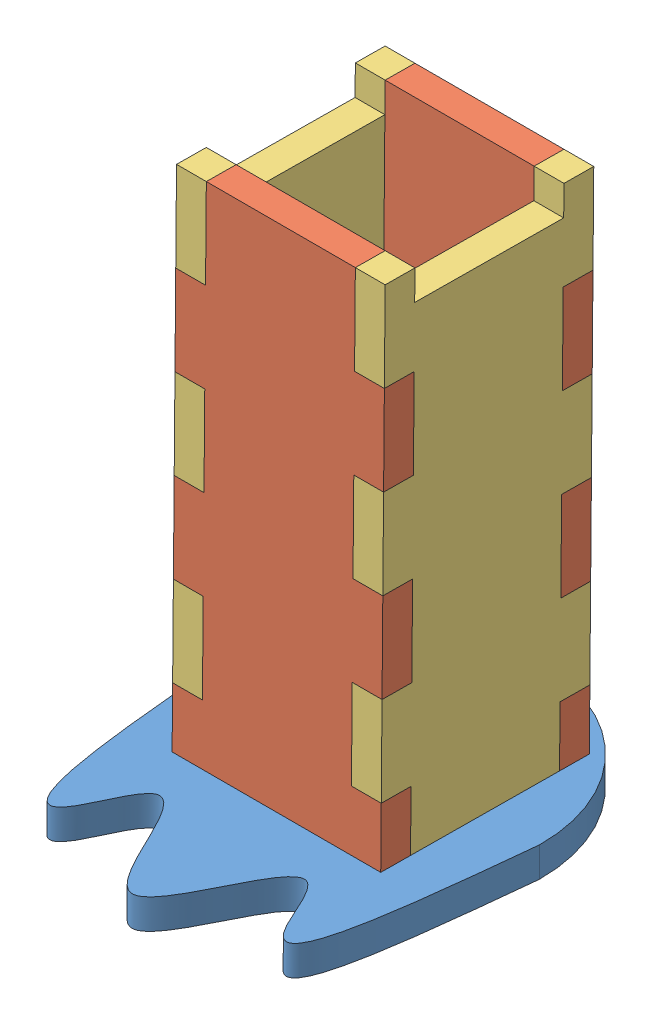
SolidWorks assembly short_leg, configuration Default. Lengths in mm.
Overall size (64 108.46 82.05).
5 component instances, 3 part files, 12 mates.
Components (placement in the parent):
- foot-1: foot [Default] at (-37.6359 -18.0496 -13.4582) x (1 0 0) z (0 -0.999962 0.008727) size (64 82 6)
- short_leg_front-1: short_leg_front [Default] at (48.8798 -33.2664 47.6015) x (-1 0 0) z (0 -0.008727 -0.999962) size (42 108 6)
- short_leg_right-1: short_leg_right [Default] at (29.3804 -31.3727 -13.2389) x (0 0.008727 0.999962) z (-1 0 0) size (42 108 6)
- short_leg_front-2: short_leg_front [Default] at (-32.119 -33.6329 5.6031) x (1 0 0) z (0 0.008727 0.999962) size (42 108 6)
- short_leg_right-2: short_leg_right [Default] at (-12.6196 -30.6777 66.4012) x (0 -0.008727 -0.999962) z (1 0 0) size (42 108 6)
Mates (geometry in assembly coordinates):
- Coincident1: coincident anti-aligned: plane of short_leg_front-1 through (-6.6196 48.4272 40.8883) normal (-1 0 0); plane of short_leg_right-2 through (-6.6196 -30.6777 66.4012) normal (1 0 0)
- Coincident2: coincident anti-aligned: plane of short_leg_front-1 through (-6.6196 48.4272 40.8883) normal (0 -0.999962 0.008727); plane of short_leg_right-2 through (-6.6196 48.4795 46.8881) normal (0 0.999962 -0.008727)
- Coincident3: coincident anti-aligned: plane of short_leg_front-1 through (48.8798 -33.3187 41.6017) normal (0 -0.008727 -0.999962); plane of short_leg_right-2 through (-6.6196 66.4265 40.7313) normal (0 0.008727 0.999962)
- Coincident4: coincident anti-aligned: plane of short_leg_front-1 through (23.3804 48.4272 40.8883) normal (1 0 0); plane of short_leg_right-1 through (23.3804 -31.3727 -13.2389) normal (-1 0 0)
- Coincident5: coincident anti-aligned: plane of short_leg_front-1 through (48.8798 -33.3187 41.6017) normal (0 -0.008727 -0.999962); plane of short_leg_right-1 through (23.3804 66.4265 40.7313) normal (0 0.008727 0.999962)
- Coincident6: coincident anti-aligned: plane of short_leg_front-1 through (29.3804 12.4285 41.2025) normal (0 -0.999962 0.008727); plane of short_leg_right-1 through (23.3804 12.4285 41.2025) normal (0 0.999962 -0.008727)
- Coincident7: coincident anti-aligned: plane of short_leg_front-2 through (-32.119 -33.5805 11.6029) normal (0 0.008727 0.999962); plane of short_leg_right-2 through (-6.6196 66.1647 10.7324) normal (0 -0.008727 -0.999962)
- Coincident8: coincident anti-aligned: plane of short_leg_front-2 through (-6.6196 12.1667 11.2036) normal (-1 0 0); plane of short_leg_right-2 through (-6.6196 -30.6777 66.4012) normal (1 0 0)
- Coincident9: coincident anti-aligned: plane of short_leg_right-1 through (23.3804 -5.8849 5.3609) normal (0 -0.999962 0.008727); plane of short_leg_front-2 through (23.3804 -5.8326 11.3607) normal (0 0.999962 -0.008727)
- Coincident11: coincident aligned: plane of foot-1 through (8.3804 -23.2647 76.5153) normal (0 -0.999962 0.008727); plane of short_leg_front-2 through (-12.6196 -23.8319 11.5178) normal (0 -0.999962 0.008727)
- Coincident12: coincident anti-aligned: plane of foot-1 through (-37.6359 -23.5177 47.5164) normal (0 -0.008727 -0.999962); plane of short_leg_front-1 through (48.8798 -33.2664 47.6015) normal (0 0.008727 0.999962)
- Coincident13: coincident anti-aligned: plane of foot-1 through (-12.6196 -24.0494 -13.4059) normal (1 0 0); plane of short_leg_right-2 through (-12.6196 -30.6777 66.4012) normal (-1 0 0)
